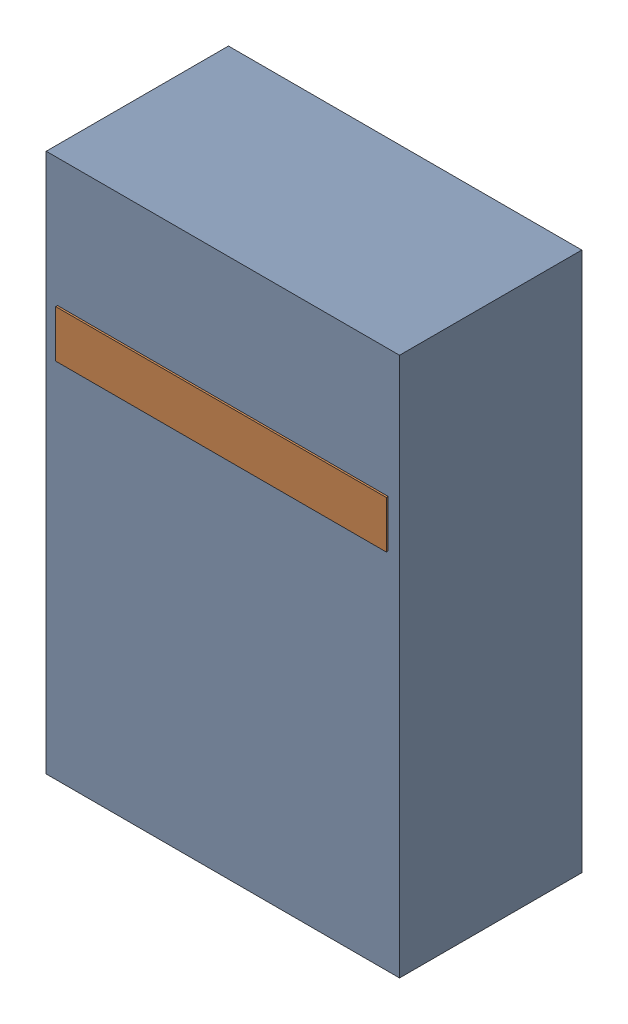
SolidWorks assembly D14, configuration Default. Lengths in mm.
Overall size (1.9 2.9 0.99).
4 component instances, 2 part files, 0 mates.
Components (placement in the parent):
- 1151710376-1: 1151710376 [Default] at (122.047 62.357 0) size (1.9 2.9 0.98)
  - Extruded-1: Extruded [Default] at origin size (1.9 2.9 0.98)
- 1151710512-1: 1151710512 [Default] at (122.047 62.992 0.95) size (1.78 0.25 0.04)
  - Extruded_1-1: Extruded_1 [Default] at origin size (1.78 0.25 0.04)
